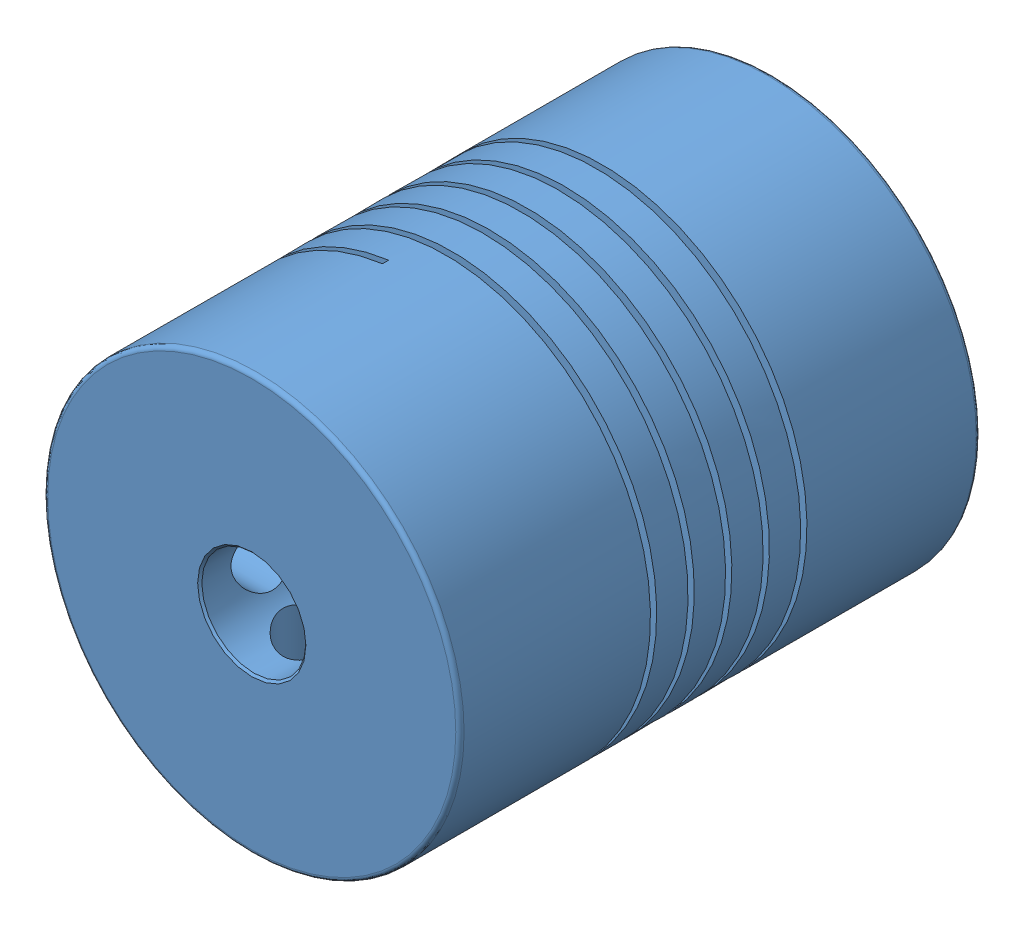
SolidWorks assembly Acople Flexible5.5, configuration Default. Lengths in mm.
Overall size (20.86 20.77 25).
5 component instances, 2 part files, 4 mates.
Components (placement in the parent):
- Acople Flexible 5.5-1: Acople Flexible 5.5 [Predeterminado] at (-123.3071 59.8391 -12.5) size (20.77 20.77 25)
- socket set screw cone point_am-1: socket set screw cone point_am [B18.3.6M - M3 x 0.5 x 6 Hex Socket Cone Pt. SS --N] at (-133.7812 59.8391 9.5) x (1 0 0) z (0 0.199151 0.979969) size (6 3 3)
- socket set screw cone point_am-3: socket set screw cone point_am [B18.3.6M - M3 x 0.5 x 6 Hex Socket Cone Pt. SS --N] at (-123.3071 49.5232 -9.5) x (0 1 0) z (-0.430549 0 0.902567) size (6 3 3)
- socket set screw cone point_am-5: socket set screw cone point_am [B18.3.6M - M3 x 0.5 x 6 Hex Socket Cone Pt. SS --N] at (-123.3071 49.5452 9.5) x (0 1 0) z (0.224681 0 0.974432) size (6 3 3)
- socket set screw cone point_am-7: socket set screw cone point_am [B18.3.6M - M3 x 0.5 x 6 Hex Socket Cone Pt. SS --N] at (-133.6418 59.8391 -9.5) x (1 0 0) z (0 -0.210117 0.977676) size (6 3 3)
Mates (geometry in assembly coordinates):
- Concentric1: concentric anti-aligned: cylinder of Acople Flexible 5.5-1 through (-123.3071 41.8391 9.5) axis (0 1 0) radius 1.5; cylinder of socket set screw cone point_am-5 through (-123.3071 36.8452 9.5) axis (0 -1 0) radius 1.5
- Concentric2: concentric anti-aligned: cylinder of Acople Flexible 5.5-1 through (-123.3071 41.8391 -9.5) axis (0 1 0) radius 1.5; cylinder of socket set screw cone point_am-3 through (-123.3071 36.8232 -9.5) axis (0 -1 0) radius 1.5
- Concentric3: concentric anti-aligned: cylinder of Acople Flexible 5.5-1 through (-283.3071 59.8391 -9.5) axis (1 0 0) radius 1.5; cylinder of socket set screw cone point_am-7 through (-146.3418 59.8391 -9.5) axis (-1 0 0) radius 1.5
- Concentric4: concentric anti-aligned: cylinder of Acople Flexible 5.5-1 through (-283.3071 59.8391 9.5) axis (1 0 0) radius 1.5; cylinder of socket set screw cone point_am-1 through (-146.4812 59.8391 9.5) axis (-1 0 0) radius 1.5
